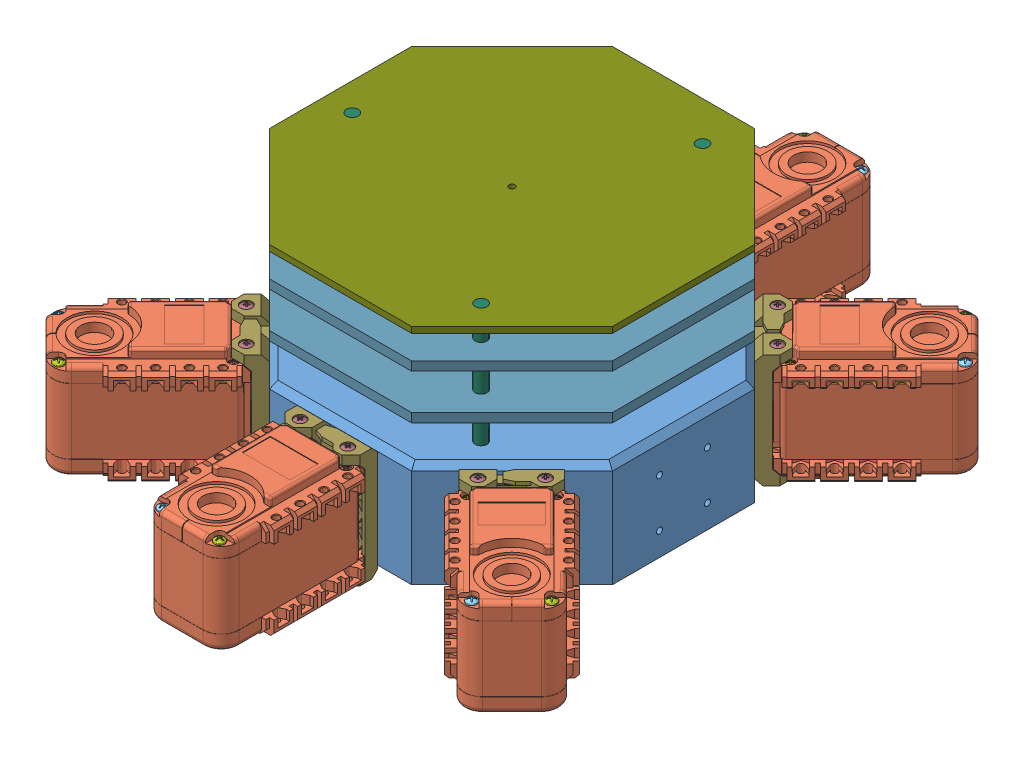
SolidWorks assembly corps, configuration Défaut. Lengths in mm.
Overall size (179.03 78.41 221.08).
134 component instances, 17 part files, 9 mates.
Components (placement in the parent):
- embase-1: embase [Défaut] at (7.1024 -18.3332 0) size (115 35 115)
- AX-12A-1: AX-12A [Défaut] at (7.361 -1.0881 99.9226) x (-1 0 0) z (0 1 0) size (32 53.04 38.67)
  - ASSY_DUMMY___-1: ASSY_DUMMY___ [Défaut] at (0.3086 -0.9226 -1.3151) size (32 50.04 38.67)
  - DC04_B01_INSERT_M3-1: DC04_B01_INSERT_M3 [Défaut] at (0.3086 -0.9226 -1.3151) size (4.98 4.98 7)
  - DX124_SCREW-COVER___-1: DX124_SCREW-COVER___ [Défaut] at (0.3086 -0.9226 -1.3151) size (3.56 3.56 30.67)
    - DX124_SCREW-COVER___-1: DX124_SCREW-COVER___ [Défaut] at origin size (2 2 6)
    - DX124_SCREW-COVER___-1-1: DX124_SCREW-COVER___-1 [Défaut] at origin size (3.56 3.56 30.67)
  - DX124_SCREW-COVER____1-1: DX124_SCREW-COVER____1 [Défaut] at (0.3086 -0.9226 -1.3151) size (3.56 3.56 30.67)
    - DX124_SCREW-COVER____1-1: DX124_SCREW-COVER____1 [Défaut] at origin size (2 2 6)
    - DX124_SCREW-COVER____1-1-1: DX124_SCREW-COVER____1-1 [Défaut] at origin size (3.56 3.56 30.67)
  - DX124_SCREW-COVER____2-1: DX124_SCREW-COVER____2 [Défaut] at (0.3086 -0.9226 -1.3151) size (3.56 3.56 30.67)
    - DX124_SCREW-COVER____2-1: DX124_SCREW-COVER____2 [Défaut] at origin size (2 2 6)
    - DX124_SCREW-COVER____2-1-1: DX124_SCREW-COVER____2-1 [Défaut] at origin size (3.56 3.56 30.67)
  - DX124_SCREW-COVER____3-1: DX124_SCREW-COVER____3 [Défaut] at (0.3086 -0.9226 -1.3151) size (3.56 3.56 30.67)
    - DX124_SCREW-COVER____3-1: DX124_SCREW-COVER____3 [Défaut] at origin size (2 2 6)
    - DX124_SCREW-COVER____3-1-1: DX124_SCREW-COVER____3-1 [Défaut] at origin size (3.56 3.56 30.67)
  - Pièce1^AX-12A-1: Pièce1^AX-12A [Défaut] at origin (virtual)
  - F3-1: F3 [Défaut] at (0.3086 -42.4226 -1.3151) size (25 9 38)
  - vis M2-3: vis M2 [B18.6.7M - M2 x 0.4 x 2.5 Type I Cross Recessed PHMS --2.5N] at (-7.6914 -36.9226 17.8849) x (0 0 -1) z (1 0 0) size (4.08 4 4)
  - vis M2-4: vis M2 [B18.6.7M - M2 x 0.4 x 2.5 Type I Cross Recessed PHMS --2.5N] at (8.3086 -36.9226 17.8849) x (0 0 -1) z (1 0 0) size (4.08 4 4)
  - vis M2-5: vis M2 [B18.6.7M - M2 x 0.4 x 2.5 Type I Cross Recessed PHMS --2.5N] at (8.3086 -36.9226 -20.5151) x (0 0 1) z (-0.923728 -0.383049 0) size (4.08 4 4)
  - vis M2-6: vis M2 [B18.6.7M - M2 x 0.4 x 2.5 Type I Cross Recessed PHMS --2.5N] at (-7.6914 -36.9226 -20.5151) x (0 0 1) z (-0.923728 -0.383049 0) size (4.08 4 4)
- AX-12A-2: AX-12A [Défaut] at (77.9412 -1.0881 70.4731) x (-0.707107 0 0.707107) z (0 1 0) size (32 53.04 38.67)
  - ASSY_DUMMY___-1: ASSY_DUMMY___ [Défaut] at (0.3086 -0.9226 -1.3151) size (32 50.04 38.67)
  - DC04_B01_INSERT_M3-1: DC04_B01_INSERT_M3 [Défaut] at (0.3086 -0.9226 -1.3151) size (4.98 4.98 7)
  - DX124_SCREW-COVER___-1: DX124_SCREW-COVER___ [Défaut] at (0.3086 -0.9226 -1.3151) size (3.56 3.56 30.67)
    - DX124_SCREW-COVER___-1: DX124_SCREW-COVER___ [Défaut] at origin size (2 2 6)
    - DX124_SCREW-COVER___-1-1: DX124_SCREW-COVER___-1 [Défaut] at origin size (3.56 3.56 30.67)
  - DX124_SCREW-COVER____1-1: DX124_SCREW-COVER____1 [Défaut] at (0.3086 -0.9226 -1.3151) size (3.56 3.56 30.67)
    - DX124_SCREW-COVER____1-1: DX124_SCREW-COVER____1 [Défaut] at origin size (2 2 6)
    - DX124_SCREW-COVER____1-1-1: DX124_SCREW-COVER____1-1 [Défaut] at origin size (3.56 3.56 30.67)
  - DX124_SCREW-COVER____2-1: DX124_SCREW-COVER____2 [Défaut] at (0.3086 -0.9226 -1.3151) size (3.56 3.56 30.67)
    - DX124_SCREW-COVER____2-1: DX124_SCREW-COVER____2 [Défaut] at origin size (2 2 6)
    - DX124_SCREW-COVER____2-1-1: DX124_SCREW-COVER____2-1 [Défaut] at origin size (3.56 3.56 30.67)
  - DX124_SCREW-COVER____3-1: DX124_SCREW-COVER____3 [Défaut] at (0.3086 -0.9226 -1.3151) size (3.56 3.56 30.67)
    - DX124_SCREW-COVER____3-1: DX124_SCREW-COVER____3 [Défaut] at origin size (2 2 6)
    - DX124_SCREW-COVER____3-1-1: DX124_SCREW-COVER____3-1 [Défaut] at origin size (3.56 3.56 30.67)
  - Pièce1^AX-12A-1: Pièce1^AX-12A [Défaut] at origin (virtual)
  - F3-1: F3 [Défaut] at (0.3086 -42.4226 -1.3151) size (25 9 38)
  - vis M2-3: vis M2 [B18.6.7M - M2 x 0.4 x 2.5 Type I Cross Recessed PHMS --2.5N] at (-7.6914 -36.9226 17.8849) x (0 0 -1) z (1 0 0) size (4.08 4 4)
  - vis M2-4: vis M2 [B18.6.7M - M2 x 0.4 x 2.5 Type I Cross Recessed PHMS --2.5N] at (8.3086 -36.9226 17.8849) x (0 0 -1) z (1 0 0) size (4.08 4 4)
  - vis M2-5: vis M2 [B18.6.7M - M2 x 0.4 x 2.5 Type I Cross Recessed PHMS --2.5N] at (8.3086 -36.9226 -20.5151) x (0 0 1) z (-0.923728 -0.383049 0) size (4.08 4 4)
  - vis M2-6: vis M2 [B18.6.7M - M2 x 0.4 x 2.5 Type I Cross Recessed PHMS --2.5N] at (-7.6914 -36.9226 -20.5151) x (0 0 1) z (-0.923728 -0.383049 0) size (4.08 4 4)
- AX-12A-3: AX-12A [Défaut] at (77.5755 -1.0881 -70.8388) x (0.707107 0 0.707107) z (0 1 0) size (32 53.04 38.67)
  - ASSY_DUMMY___-1: ASSY_DUMMY___ [Défaut] at (0.3086 -0.9226 -1.3151) size (32 50.04 38.67)
  - DC04_B01_INSERT_M3-1: DC04_B01_INSERT_M3 [Défaut] at (0.3086 -0.9226 -1.3151) size (4.98 4.98 7)
  - DX124_SCREW-COVER___-1: DX124_SCREW-COVER___ [Défaut] at (0.3086 -0.9226 -1.3151) size (3.56 3.56 30.67)
    - DX124_SCREW-COVER___-1: DX124_SCREW-COVER___ [Défaut] at origin size (2 2 6)
    - DX124_SCREW-COVER___-1-1: DX124_SCREW-COVER___-1 [Défaut] at origin size (3.56 3.56 30.67)
  - DX124_SCREW-COVER____1-1: DX124_SCREW-COVER____1 [Défaut] at (0.3086 -0.9226 -1.3151) size (3.56 3.56 30.67)
    - DX124_SCREW-COVER____1-1: DX124_SCREW-COVER____1 [Défaut] at origin size (2 2 6)
    - DX124_SCREW-COVER____1-1-1: DX124_SCREW-COVER____1-1 [Défaut] at origin size (3.56 3.56 30.67)
  - DX124_SCREW-COVER____2-1: DX124_SCREW-COVER____2 [Défaut] at (0.3086 -0.9226 -1.3151) size (3.56 3.56 30.67)
    - DX124_SCREW-COVER____2-1: DX124_SCREW-COVER____2 [Défaut] at origin size (2 2 6)
    - DX124_SCREW-COVER____2-1-1: DX124_SCREW-COVER____2-1 [Défaut] at origin size (3.56 3.56 30.67)
  - DX124_SCREW-COVER____3-1: DX124_SCREW-COVER____3 [Défaut] at (0.3086 -0.9226 -1.3151) size (3.56 3.56 30.67)
    - DX124_SCREW-COVER____3-1: DX124_SCREW-COVER____3 [Défaut] at origin size (2 2 6)
    - DX124_SCREW-COVER____3-1-1: DX124_SCREW-COVER____3-1 [Défaut] at origin size (3.56 3.56 30.67)
  - Pièce1^AX-12A-1: Pièce1^AX-12A [Défaut] at origin (virtual)
  - F3-1: F3 [Défaut] at (0.3086 -42.4226 -1.3151) size (25 9 38)
  - vis M2-3: vis M2 [B18.6.7M - M2 x 0.4 x 2.5 Type I Cross Recessed PHMS --2.5N] at (-7.6914 -36.9226 17.8849) x (0 0 -1) z (1 0 0) size (4.08 4 4)
  - vis M2-4: vis M2 [B18.6.7M - M2 x 0.4 x 2.5 Type I Cross Recessed PHMS --2.5N] at (8.3086 -36.9226 17.8849) x (0 0 -1) z (1 0 0) size (4.08 4 4)
  - vis M2-5: vis M2 [B18.6.7M - M2 x 0.4 x 2.5 Type I Cross Recessed PHMS --2.5N] at (8.3086 -36.9226 -20.5151) x (0 0 1) z (-0.923728 -0.383049 0) size (4.08 4 4)
  - vis M2-6: vis M2 [B18.6.7M - M2 x 0.4 x 2.5 Type I Cross Recessed PHMS --2.5N] at (-7.6914 -36.9226 -20.5151) x (0 0 1) z (-0.923728 -0.383049 0) size (4.08 4 4)
- AX-12A-4: AX-12A [Défaut] at (6.8439 -1.0881 -99.9226) x (1 0 0) z (0 1 0) size (32 53.04 38.67)
  - ASSY_DUMMY___-1: ASSY_DUMMY___ [Défaut] at (0.3086 -0.9226 -1.3151) size (32 50.04 38.67)
  - DC04_B01_INSERT_M3-1: DC04_B01_INSERT_M3 [Défaut] at (0.3086 -0.9226 -1.3151) size (4.98 4.98 7)
  - DX124_SCREW-COVER___-1: DX124_SCREW-COVER___ [Défaut] at (0.3086 -0.9226 -1.3151) size (3.56 3.56 30.67)
    - DX124_SCREW-COVER___-1: DX124_SCREW-COVER___ [Défaut] at origin size (2 2 6)
    - DX124_SCREW-COVER___-1-1: DX124_SCREW-COVER___-1 [Défaut] at origin size (3.56 3.56 30.67)
  - DX124_SCREW-COVER____1-1: DX124_SCREW-COVER____1 [Défaut] at (0.3086 -0.9226 -1.3151) size (3.56 3.56 30.67)
    - DX124_SCREW-COVER____1-1: DX124_SCREW-COVER____1 [Défaut] at origin size (2 2 6)
    - DX124_SCREW-COVER____1-1-1: DX124_SCREW-COVER____1-1 [Défaut] at origin size (3.56 3.56 30.67)
  - DX124_SCREW-COVER____2-1: DX124_SCREW-COVER____2 [Défaut] at (0.3086 -0.9226 -1.3151) size (3.56 3.56 30.67)
    - DX124_SCREW-COVER____2-1: DX124_SCREW-COVER____2 [Défaut] at origin size (2 2 6)
    - DX124_SCREW-COVER____2-1-1: DX124_SCREW-COVER____2-1 [Défaut] at origin size (3.56 3.56 30.67)
  - DX124_SCREW-COVER____3-1: DX124_SCREW-COVER____3 [Défaut] at (0.3086 -0.9226 -1.3151) size (3.56 3.56 30.67)
    - DX124_SCREW-COVER____3-1: DX124_SCREW-COVER____3 [Défaut] at origin size (2 2 6)
    - DX124_SCREW-COVER____3-1-1: DX124_SCREW-COVER____3-1 [Défaut] at origin size (3.56 3.56 30.67)
  - Pièce1^AX-12A-1: Pièce1^AX-12A [Défaut] at origin (virtual)
  - F3-1: F3 [Défaut] at (0.3086 -42.4226 -1.3151) size (25 9 38)
  - vis M2-3: vis M2 [B18.6.7M - M2 x 0.4 x 2.5 Type I Cross Recessed PHMS --2.5N] at (-7.6914 -36.9226 17.8849) x (0 0 -1) z (1 0 0) size (4.08 4 4)
  - vis M2-4: vis M2 [B18.6.7M - M2 x 0.4 x 2.5 Type I Cross Recessed PHMS --2.5N] at (8.3086 -36.9226 17.8849) x (0 0 -1) z (1 0 0) size (4.08 4 4)
  - vis M2-5: vis M2 [B18.6.7M - M2 x 0.4 x 2.5 Type I Cross Recessed PHMS --2.5N] at (8.3086 -36.9226 -20.5151) x (0 0 1) z (-0.923728 -0.383049 0) size (4.08 4 4)
  - vis M2-6: vis M2 [B18.6.7M - M2 x 0.4 x 2.5 Type I Cross Recessed PHMS --2.5N] at (-7.6914 -36.9226 -20.5151) x (0 0 1) z (-0.923728 -0.383049 0) size (4.08 4 4)
- AX-12A-5: AX-12A [Défaut] at (-63.7363 -1.0881 -70.4731) x (0.707107 0 -0.707107) z (0 1 0) size (32 53.04 38.67)
  - ASSY_DUMMY___-1: ASSY_DUMMY___ [Défaut] at (0.3086 -0.9226 -1.3151) size (32 50.04 38.67)
  - DC04_B01_INSERT_M3-1: DC04_B01_INSERT_M3 [Défaut] at (0.3086 -0.9226 -1.3151) size (4.98 4.98 7)
  - DX124_SCREW-COVER___-1: DX124_SCREW-COVER___ [Défaut] at (0.3086 -0.9226 -1.3151) size (3.56 3.56 30.67)
    - DX124_SCREW-COVER___-1: DX124_SCREW-COVER___ [Défaut] at origin size (2 2 6)
    - DX124_SCREW-COVER___-1-1: DX124_SCREW-COVER___-1 [Défaut] at origin size (3.56 3.56 30.67)
  - DX124_SCREW-COVER____1-1: DX124_SCREW-COVER____1 [Défaut] at (0.3086 -0.9226 -1.3151) size (3.56 3.56 30.67)
    - DX124_SCREW-COVER____1-1: DX124_SCREW-COVER____1 [Défaut] at origin size (2 2 6)
    - DX124_SCREW-COVER____1-1-1: DX124_SCREW-COVER____1-1 [Défaut] at origin size (3.56 3.56 30.67)
  - DX124_SCREW-COVER____2-1: DX124_SCREW-COVER____2 [Défaut] at (0.3086 -0.9226 -1.3151) size (3.56 3.56 30.67)
    - DX124_SCREW-COVER____2-1: DX124_SCREW-COVER____2 [Défaut] at origin size (2 2 6)
    - DX124_SCREW-COVER____2-1-1: DX124_SCREW-COVER____2-1 [Défaut] at origin size (3.56 3.56 30.67)
  - DX124_SCREW-COVER____3-1: DX124_SCREW-COVER____3 [Défaut] at (0.3086 -0.9226 -1.3151) size (3.56 3.56 30.67)
    - DX124_SCREW-COVER____3-1: DX124_SCREW-COVER____3 [Défaut] at origin size (2 2 6)
    - DX124_SCREW-COVER____3-1-1: DX124_SCREW-COVER____3-1 [Défaut] at origin size (3.56 3.56 30.67)
  - Pièce1^AX-12A-1: Pièce1^AX-12A [Défaut] at origin (virtual)
  - F3-1: F3 [Défaut] at (0.3086 -42.4226 -1.3151) size (25 9 38)
  - vis M2-3: vis M2 [B18.6.7M - M2 x 0.4 x 2.5 Type I Cross Recessed PHMS --2.5N] at (-7.6914 -36.9226 17.8849) x (0 0 -1) z (1 0 0) size (4.08 4 4)
  - vis M2-4: vis M2 [B18.6.7M - M2 x 0.4 x 2.5 Type I Cross Recessed PHMS --2.5N] at (8.3086 -36.9226 17.8849) x (0 0 -1) z (1 0 0) size (4.08 4 4)
  - vis M2-5: vis M2 [B18.6.7M - M2 x 0.4 x 2.5 Type I Cross Recessed PHMS --2.5N] at (8.3086 -36.9226 -20.5151) x (0 0 1) z (-0.923728 -0.383049 0) size (4.08 4 4)
  - vis M2-6: vis M2 [B18.6.7M - M2 x 0.4 x 2.5 Type I Cross Recessed PHMS --2.5N] at (-7.6914 -36.9226 -20.5151) x (0 0 1) z (-0.923728 -0.383049 0) size (4.08 4 4)
- AX-12A-6: AX-12A [Défaut] at (-63.3706 -1.0881 70.8388) x (-0.707107 0 -0.707107) z (0 1 0) size (32 53.04 38.67)
  - ASSY_DUMMY___-1: ASSY_DUMMY___ [Défaut] at (0.3086 -0.9226 -1.3151) size (32 50.04 38.67)
  - DC04_B01_INSERT_M3-1: DC04_B01_INSERT_M3 [Défaut] at (0.3086 -0.9226 -1.3151) size (4.98 4.98 7)
  - DX124_SCREW-COVER___-1: DX124_SCREW-COVER___ [Défaut] at (0.3086 -0.9226 -1.3151) size (3.56 3.56 30.67)
    - DX124_SCREW-COVER___-1: DX124_SCREW-COVER___ [Défaut] at origin size (2 2 6)
    - DX124_SCREW-COVER___-1-1: DX124_SCREW-COVER___-1 [Défaut] at origin size (3.56 3.56 30.67)
  - DX124_SCREW-COVER____1-1: DX124_SCREW-COVER____1 [Défaut] at (0.3086 -0.9226 -1.3151) size (3.56 3.56 30.67)
    - DX124_SCREW-COVER____1-1: DX124_SCREW-COVER____1 [Défaut] at origin size (2 2 6)
    - DX124_SCREW-COVER____1-1-1: DX124_SCREW-COVER____1-1 [Défaut] at origin size (3.56 3.56 30.67)
  - DX124_SCREW-COVER____2-1: DX124_SCREW-COVER____2 [Défaut] at (0.3086 -0.9226 -1.3151) size (3.56 3.56 30.67)
    - DX124_SCREW-COVER____2-1: DX124_SCREW-COVER____2 [Défaut] at origin size (2 2 6)
    - DX124_SCREW-COVER____2-1-1: DX124_SCREW-COVER____2-1 [Défaut] at origin size (3.56 3.56 30.67)
  - DX124_SCREW-COVER____3-1: DX124_SCREW-COVER____3 [Défaut] at (0.3086 -0.9226 -1.3151) size (3.56 3.56 30.67)
    - DX124_SCREW-COVER____3-1: DX124_SCREW-COVER____3 [Défaut] at origin size (2 2 6)
    - DX124_SCREW-COVER____3-1-1: DX124_SCREW-COVER____3-1 [Défaut] at origin size (3.56 3.56 30.67)
  - Pièce1^AX-12A-1: Pièce1^AX-12A [Défaut] at origin (virtual)
  - F3-1: F3 [Défaut] at (0.3086 -42.4226 -1.3151) size (25 9 38)
  - vis M2-3: vis M2 [B18.6.7M - M2 x 0.4 x 2.5 Type I Cross Recessed PHMS --2.5N] at (-7.6914 -36.9226 17.8849) x (0 0 -1) z (1 0 0) size (4.08 4 4)
  - vis M2-4: vis M2 [B18.6.7M - M2 x 0.4 x 2.5 Type I Cross Recessed PHMS --2.5N] at (8.3086 -36.9226 17.8849) x (0 0 -1) z (1 0 0) size (4.08 4 4)
  - vis M2-5: vis M2 [B18.6.7M - M2 x 0.4 x 2.5 Type I Cross Recessed PHMS --2.5N] at (8.3086 -36.9226 -20.5151) x (0 0 1) z (-0.923728 -0.383049 0) size (4.08 4 4)
  - vis M2-6: vis M2 [B18.6.7M - M2 x 0.4 x 2.5 Type I Cross Recessed PHMS --2.5N] at (-7.6914 -36.9226 -20.5151) x (0 0 1) z (-0.923728 -0.383049 0) size (4.08 4 4)
- carte avec support-1: carte avec support [Défaut] at (10.6403 41.3759 0) size (115 40 115)
  - carte-1: carte [Défaut] at (-3.5379 2.2909 0) size (115 3 115)
  - axe carte-1: axe carte [Défaut] at (35.8948 -24.7091 42.8197) x (1 0 0) z (0 1 0) size (4 4 40)
  - axe carte-2: axe carte [Défaut] at (26.6571 -24.7091 -40.6877) x (1 0 0) z (0 1 0) size (4 4 40)
  - axe carte-3: axe carte [Défaut] at (-41.0435 -24.7091 9.0661) x (1 0 0) z (0 1 0) size (4 4 40)
  - carte-2: carte [Défaut] at (-3.5379 -12.7091 0) size (115 3 115)
- couvercle-1: couvercle [Défaut] at (7.1024 54.6668 0) size (115 2 115)
Mates (geometry in assembly coordinates):
- Coaxiale3: concentric aligned: cylinder of embase-1 through (-0.9476 5.5968 -57.5) axis (0 0 1) radius 1; cylinder of AX-12A-1/F3-1 through (-0.9476 5.5968 59.5) axis (0 0 1) radius 1.05
- Coïncidente4: coincident anti-aligned: plane of embase-1 through (-16.7148 16.6668 57.5) normal (0 0 1); plane of AX-12A-1/F3-1 through (3.5524 -21.4032 57.5) normal (0 0 -1)
- Parallèle2: parallel aligned: plane of embase-1 through (7.1024 16.6668 -81.3173) normal (0 1 0); plane of AX-12A-1/F3-1 through (20.0524 16.5968 59.36) normal (0 1 0)
- Coïncidente23: coincident aligned: plane of embase-1 through (7.1024 16.6668 -81.3173) normal (0 1 0); circle of carte avec support-1/axe carte-3
- Coïncidente24: coincident aligned: plane of embase-1 through (-50.3976 16.6668 -23.8173) normal (-1 0 0); plane of carte avec support-1/carte-1 through (-50.3976 46.6668 -23.8173) normal (-1 0 0)
- Coïncidente25: coincident aligned: plane of embase-1 through (30.9197 16.6668 -57.5) normal (0 0 -1); plane of carte avec support-1/carte-1 through (30.9197 46.6668 -57.5) normal (0 0 -1)
- Coïncidente26: coincident aligned: plane of carte avec support-1/axe carte-1 through (35.8278 56.6668 39.087) normal (0 1 0); plane of couvercle-1 through (7.1024 56.6668 -81.3173) normal (0 1 0)
- Coaxiale22: concentric anti-aligned: cylinder of carte avec support-1/axe carte-1 through (35.8278 56.6668 39.087) axis (0 -1 0) radius 2; cylinder of couvercle-1 through (35.8278 54.6668 39.087) axis (0 1 0) radius 2
- Coïncidente27: coincident aligned: plane of carte avec support-1/carte-1 through (-50.3976 46.6668 -23.8173) normal (-1 0 0); plane of couvercle-1 through (-50.3976 56.6668 -23.8173) normal (-1 0 0)
